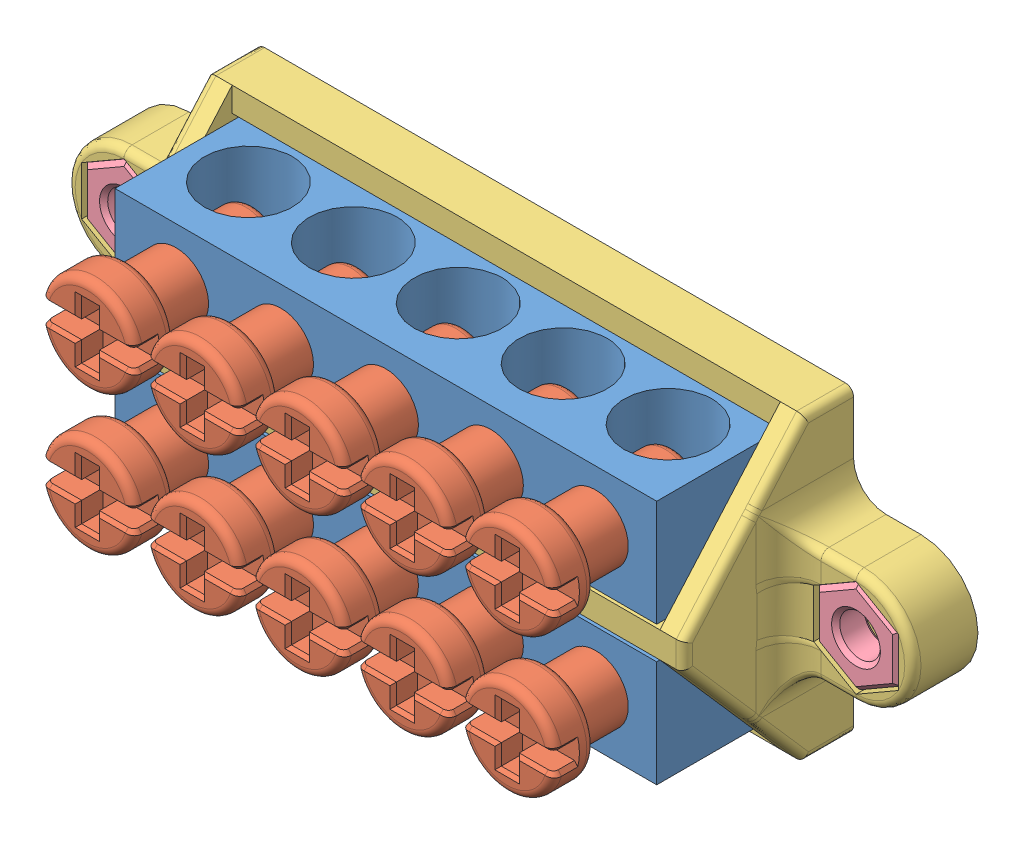
SolidWorks assembly bus-bar-dual-with-mount, configuration Default. Lengths in mm.
Overall size (52 18.5 15.85).
17 component instances, 4 part files, 13 mates.
Components (placement in the parent):
- bus-bar-1: bus-bar [Default] x (1 0 0) z (0 0 -1) size (33.3 6.55 14.35)
  - bus-bar-body-1: bus-bar-body [Default] at origin size (33.3 6.55 8.9)
  - bus-bar-screw-1: bus-bar-screw [Default] at (-12.9 3.275 0.35) x (0 1 0) z (-1 0 0) size (5.9 10.25 5.9)
  - bus-bar-screw-2: bus-bar-screw [Default] at (-6.45 3.275 0.35) x (0 1 0) z (-1 0 0) size (5.9 10.25 5.9)
  - bus-bar-screw-3: bus-bar-screw [Default] at (0 3.275 0.35) x (0 1 0) z (-1 0 0) size (5.9 10.25 5.9)
  - bus-bar-screw-4: bus-bar-screw [Default] at (6.45 3.275 0.35) x (0 1 0) z (-1 0 0) size (5.9 10.25 5.9)
  - bus-bar-screw-5: bus-bar-screw [Default] at (12.9 3.275 0.35) x (0 1 0) z (-1 0 0) size (5.9 10.25 5.9)
- bus-bar-2: bus-bar [Default] at (0 8.55 0) x (1 0 0) z (0 0 -1) size (33.3 6.55 14.35)
  - bus-bar-body-1: bus-bar-body [Default] at origin size (33.3 6.55 8.9)
  - bus-bar-screw-1: bus-bar-screw [Default] at (-12.9 3.275 0.35) x (0 1 0) z (-1 0 0) size (5.9 10.25 5.9)
  - bus-bar-screw-2: bus-bar-screw [Default] at (-6.45 3.275 0.35) x (0 1 0) z (-1 0 0) size (5.9 10.25 5.9)
  - bus-bar-screw-3: bus-bar-screw [Default] at (0 3.275 0.35) x (0 1 0) z (-1 0 0) size (5.9 10.25 5.9)
  - bus-bar-screw-4: bus-bar-screw [Default] at (6.45 3.275 0.35) x (0 1 0) z (-1 0 0) size (5.9 10.25 5.9)
  - bus-bar-screw-5: bus-bar-screw [Default] at (12.9 3.275 0.35) x (0 1 0) z (-1 0 0) size (5.9 10.25 5.9)
- bus-bar-dual-mount-1: bus-bar-dual-mount [Default] at (0 0 -4.45) x (1 0 0) z (0 0 -1) size (52 18.5 10.4)
- nut-M2.5-1: nut-M2.5 [Default] at (22.5 1 -1.95) x (1 0 0) z (0 1 0) size (5 2 5.77)
- nut-M2.5-2: nut-M2.5 [Default] at (-22.5 1 -1.95) x (-1 0 0) z (0 -1 0) size (5 2 5.77)
Mates (geometry in assembly coordinates):
- Coincident1: coincident aligned: plane of bus-bar-1/bus-bar-body-1 through (-16.65 -6.55 -4.45) normal (0 0 -1); plane of bus-bar-2/bus-bar-body-1 through (-16.65 2 -4.45) normal (0 0 -1)
- Coincident2: coincident aligned: plane of bus-bar-1/bus-bar-body-1 through (16.65 -6.55 4.45) normal (1 0 0); plane of bus-bar-2/bus-bar-body-1 through (16.65 2 4.45) normal (1 0 0)
- Distance1: distance = 2 mm anti-aligned: plane of bus-bar-1/bus-bar-body-1 through (0 0 0) normal (0 1 0); plane of bus-bar-2/bus-bar-body-1 through (0 2 0) normal (0 -1 0)
- InPlace1: in place: plane of bus-bar-1/bus-bar-body-1 through (-16.65 -6.55 -4.45) normal (0 0 -1); plane of ? through (0 0 -4.45) normal (0 0 -1); moOrthogonalPlaneRef_w of bus-bar-1/bus-bar-body-1 through (-16.65 -6.55 -4.45) normal (0 0 -1); plane of ? through (0 0 -4.45) normal (0 1 0); plane of bus-bar-1/bus-bar-body-1 through (-16.65 -6.55 -4.45) normal (0 0 -1); plane of ? through (0 0 -4.45) normal (-1 0 0); plane of bus-bar-1/bus-bar-body-1 through (-16.65 -6.55 -4.45) normal (0 0 -1); unknown of bus-bar-dual-mount-1
- Coincident3: coincident aligned: plane of bus-bar-1/bus-bar-body-1; plane of bus-bar-dual-mount-1
- Coincident4: coincident aligned: moOrthogonalPlaneRef_w of bus-bar-1/bus-bar-body-1 through (0 0 -4.45) normal (0 -1 0); plane of bus-bar-dual-mount-1 through (0 0 -4.45) normal (0 -1 0)
- Coincident5: coincident anti-aligned: moOrthogonalPlaneRef_w of bus-bar-1/bus-bar-body-1 through (0 0 -4.45) normal (-1 0 0); plane of bus-bar-dual-mount-1 through (0 0 -4.45) normal (1 0 0)
- Concentric1: concentric anti-aligned: cylinder of bus-bar-dual-mount-1 through (22.5 1 -1.95) axis (0 0 -1) radius 1.35; cylinder of nut-M2.5-1 through (22.5 1 -3.95) axis (0 0 1) radius 1.25
- Coincident6: coincident anti-aligned: plane of bus-bar-dual-mount-1 through (0 0 -3.95) normal (0 0 1); plane of nut-M2.5-1 through (22.5 1 -3.95) normal (0 0 -1)
- Parallel1: parallel anti-aligned: plane of bus-bar-dual-mount-1 through (25.1 2.5011 -3.95) normal (-1 0 0); plane of nut-M2.5-1 through (25 2.4434 -3.95) normal (1 0 0)
- Concentric2: concentric anti-aligned: cylinder of bus-bar-dual-mount-1 through (-22.5 1 -1.95) axis (0 0 -1) radius 1.35; cylinder of nut-M2.5-2 through (-22.5 1 -3.95) axis (0 0 1) radius 1.25
- Coincident8: coincident anti-aligned: plane of bus-bar-dual-mount-1 through (0 0 -3.95) normal (0 0 1); plane of nut-M2.5-2 through (-22.5 1 -3.95) normal (0 0 -1)
- Parallel2: parallel anti-aligned: plane of bus-bar-dual-mount-1 through (-25.1 2.5011 -3.95) normal (1 0 0); plane of nut-M2.5-2 through (-25 -0.4434 -3.95) normal (-1 0 0)
